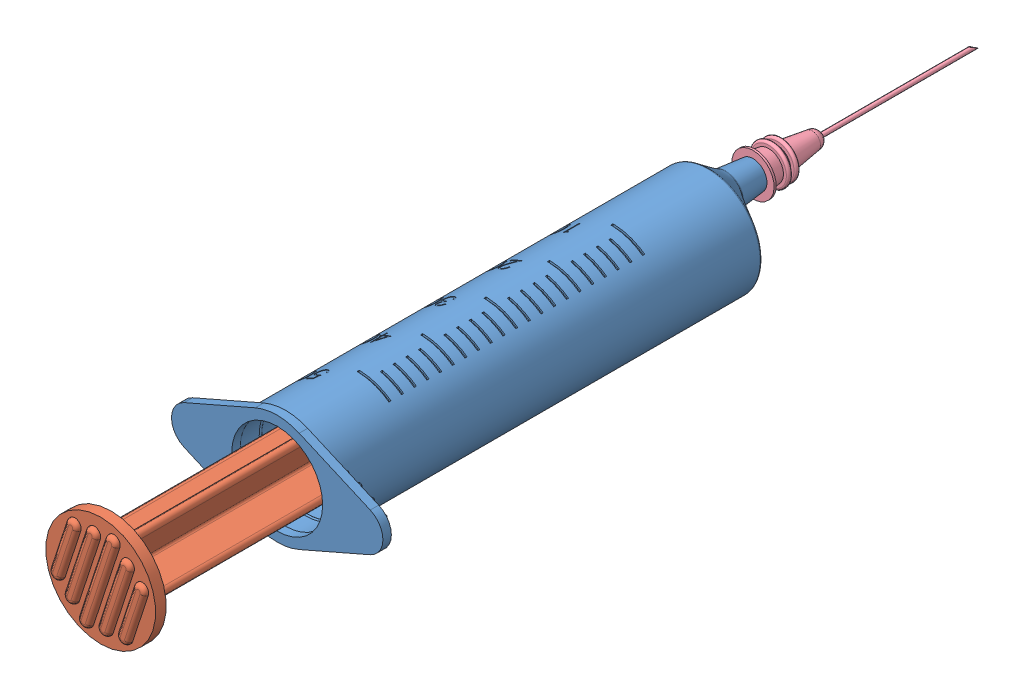
SolidWorks assembly Assem1, configuration Default. Lengths in mm.
Overall size (50 32.81 208.34).
4 component instances, 4 part files, 5 mates.
Components (placement in the parent):
- Part 1-1: Part 1 [Default] at (32.9922 53.771 157.5739) size (50 26 121)
- Part 2-1: Part 2 [Default] at (45.4922 53.771 90.8126) x (0.950221 -0.311576 0) z (-0.311576 -0.950221 0) size (26 111.5 26)
- Part 3-1: Part 3 [Default] at (45.4922 53.771 86.9846) x (-0.316183 -0.948698 0) z (-0.948698 0.316183 0) size (22 8.83 22)
- Part 4-1: Part 4 [Default] at (45.4922 59.771 33.065) x (0 0 -1) z (0.243541 -0.969891 0) size (53.1 10 10)
Mates (geometry in assembly coordinates):
- Concentric2: concentric: cylinder of assembly; cylinder of assembly; cylinder of Part 2-1 through (45.4922 53.771 96.8126) axis (0 0 1) radius 7.5; cylinder of Part 3-1 through (45.4922 53.771 90.9626) axis (0 0 -1) radius 6
- Coincident1: coincident: plane of assembly; plane of assembly; plane of Part 2-1 through (51.1935 51.9016 95.8126) normal (0 0 -1); plane of Part 3-1 through (45.4922 53.771 95.8126) normal (0 0 1)
- Concentric3: concentric: cylinder of assembly; cone of assembly; cylinder of Part 1-1 through (45.4922 53.771 159.5739) axis (0 0 1) radius 11; cone of Part 3-1 through (45.4922 53.771 90.9626) axis (0 0 -1)
- Concentric4: concentric: cone of assembly; cone of assembly; cone of Part 1-1 through (45.4922 59.771 53.5739) axis (0 0 -1); cone of Part 4-1 through (45.4922 59.771 47.065) axis (0 0 -1)
- Coincident2: coincident: cone of assembly; circle of assembly; cone of Part 1-1 through (45.4922 59.771 53.5739) axis (0 0 -1); circle of Part 4-1
